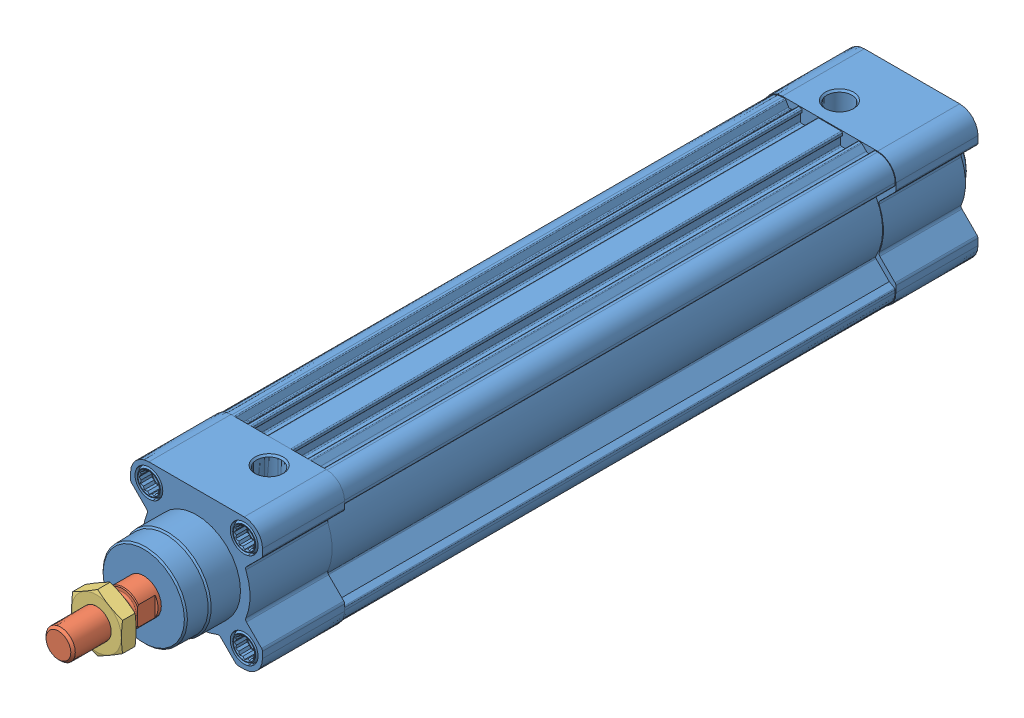
SolidWorks assembly 2123089 DSBC-32-150-PPSA-N3---(0), configuration Default. Lengths in mm.
Overall size (45 45 295.1).
3 component instances, 3 part files, 6 mates.
Components (placement in the parent):
- 1463250 DSBC-32-150-PPSA_(Z_0)-1: 1463250 DSBC-32-150-PPSA_(Z_0) [Default] at origin size (45 45 266)
- 1463250 DSBC-32-150_(K)-1: 1463250 DSBC-32-150_(K) [Default] at origin size (32 32 263.1)
- DIN-439-B - M10x1_25(F)-1: DIN-439-B - M10x1_25(F) [Default] at (0 0 34.1) x (1 0 0) z (0 -1 0) size (17 5 19.63)
Mates (geometry in assembly coordinates):
- LimitDistance1: limit distance = 0 mm anti-aligned: plane of 1463250 DSBC-32-150-PPSA_(Z_0)-1 through (0 0 -216) normal (0 0 1); plane of 1463250 DSBC-32-150_(K)-1 through (0 0 -216) normal (0 0 -1)
- Coincident1: coincident anti-aligned: line of 1463250 DSBC-32-150-PPSA_(Z_0)-1 through (0 0 80.9) axis (0 0 -1); line of 1463250 DSBC-32-150_(K)-1 through (0 0 -50) axis (0 0 1)
- Angle2: planar angle = 1.570796 rad anti-aligned: plane of 1463250 DSBC-32-150_(K)-1 through (0 0 0) normal (0 1 0); plane of 1463250 DSBC-32-150-PPSA_(Z_0)-1 through (0 0 0) normal (1 0 0)
- Distance1: distance = 0 mm anti-aligned: plane of 1463250 DSBC-32-150_(K)-1 through (0 0 34.1) normal (0 0 -1); plane of DIN-439-B - M10x1_25(F)-1 through (0 0 34.1) normal (0 0 1)
- Coincident2: coincident anti-aligned: line of 1463250 DSBC-32-150_(K)-1 through (0 0 -80.9) axis (0 0 1); line of DIN-439-B - M10x1_25(F)-1 through (0 0 84.1) axis (0 0 -1)
- Angle5: planar angle = 0 rad aligned: plane of DIN-439-B - M10x1_25(F)-1 through (0 0 34.1) normal (1 0 0); plane of 1463250 DSBC-32-150_(K)-1 through (0 0 0) normal (1 0 0)
